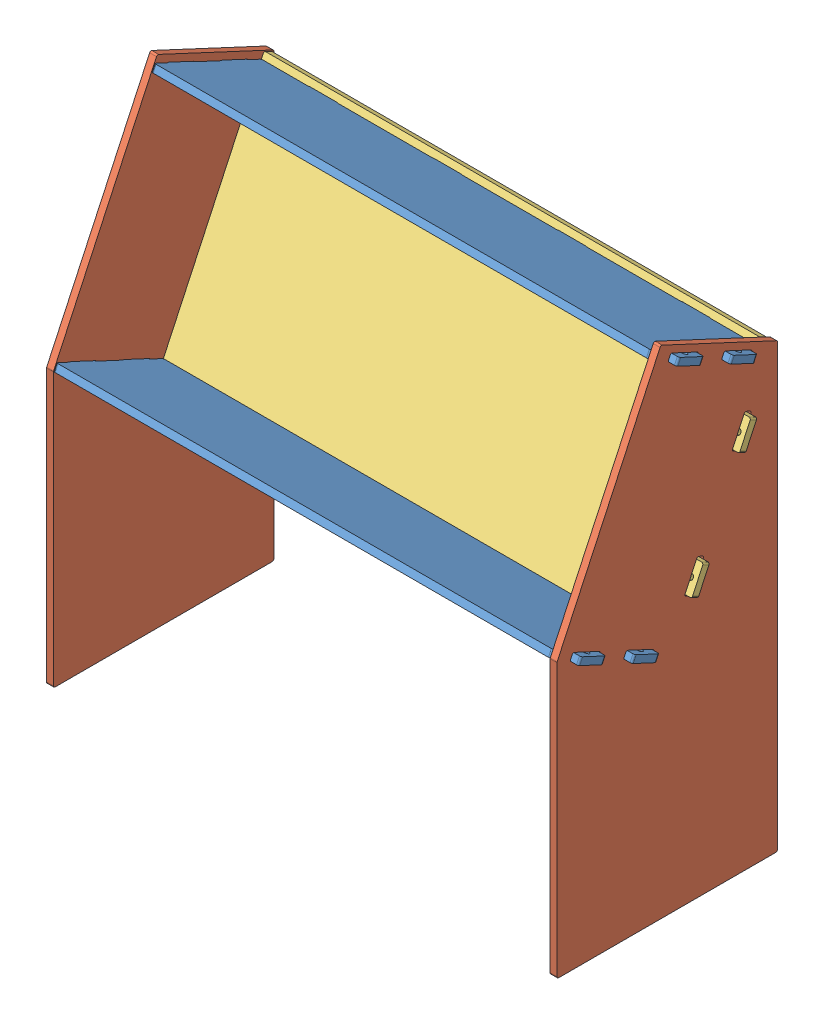
SolidWorks assembly GE-25410, configuration Default. Lengths in mm.
Overall size (971.55 1075.9 915.91).
5 component instances, 3 part files, 15 mates.
Components (placement in the parent):
- GE-25411-1: GE-25411 [30 w>] at (0 467.4625 306.7137) x (1 0 0) z (0 -0.906308 0.422618) size (971.55 244.47 12.7)
- GE-25411-2: GE-25411 [30 w>] at (0 857.1948 124.9785) x (1 0 0) z (0 -0.906308 0.422618) size (971.55 244.47 12.7)
- GE-25413-1: GE-25413 [30 w] at (466.725 708.9665 314.9598) x (0 0.906308 -0.422618) z (1 0 0) size (914.78 584.03 12.7)
- GE-25412-1: GE-25412 [30 w] at (0 613.0072 110.9774) x (1 0 0) z (0 0.422618 0.906308) size (971.55 467.36 12.7)
- GE-25413-4: GE-25413 [30 w] at (-466.725 708.9665 314.9598) x (0 0.906308 -0.422618) z (1 0 0) size (914.78 584.03 12.7)
Mates (geometry in assembly coordinates):
- Coincident1: coincident aligned: plane of Polycarb back panel-1 through (0 613.0072 110.9774) normal (1 0 0)
- Coincident2: coincident anti-aligned: plane of Side panel-1 through (473.075 0 408.672) normal (0 -1 0)
- Coincident3: coincident anti-aligned: plane of Side panel-1 through (473.075 0 0) normal (0 0 -1)
- Coincident4: coincident anti-aligned: plane of Side panel-1 through (460.375 708.9665 314.9598) normal (-1 0 0); plane of Polycarb back panel-1 through (460.375 426.925 204.7554) normal (1 0 0)
- Coincident5: coincident anti-aligned: plane of Side panel-1 through (473.075 805.1472 28.3875) normal (0 -0.422618 -0.906308); plane of Polycarb back panel-1 through (0 615.6908 116.7324) normal (0 0.422618 0.906308)
- Coincident6: coincident anti-aligned: plane of TopBottom panel-1 through (460.375 416.7567 213.0001) normal (1 0 0); plane of Side panel-1 through (460.375 708.9665 314.9598) normal (-1 0 0)
- Coincident7: coincident anti-aligned: plane of TopBottom panel-1 through (457.2 506.6582 405.7945) normal (0 -0.906308 0.422618); plane of Side panel-1 through (473.075 496.93 384.9324) normal (0 0.906308 -0.422618)
- Coincident8: coincident anti-aligned: plane of TopBottom panel-1 through (-457.2 415.4149 210.1226) normal (0 -0.422618 -0.906308); plane of Polycarb back panel-1 through (0 615.6908 116.7324) normal (0 0.422618 0.906308)
- Coincident9: coincident anti-aligned: plane of TopBottom panel-1 through (457.2 518.1683 400.4272) normal (0 0.906308 -0.422618); plane of Polycarb back panel-1 through (373.8562 421.5578 193.2453) normal (0 -0.906308 0.422618)
- Coincident10: coincident anti-aligned: plane of TopBottom panel-2 through (460.375 806.489 31.265) normal (1 0 0); plane of Side panel-1 through (460.375 708.9665 314.9598) normal (-1 0 0)
- Coincident11: coincident anti-aligned: plane of TopBottom panel-2 through (457.2 896.3905 224.0593) normal (0 -0.906308 0.422618); plane of Side panel-1 through (473.075 897.7323 226.9368) normal (0 0.906308 -0.422618)
- Coincident12: coincident anti-aligned: plane of TopBottom panel-2 through (-457.2 805.1472 28.3875) normal (0 -0.422618 -0.906308); plane of Polycarb back panel-1 through (0 615.6908 116.7324) normal (0 0.422618 0.906308)
- Coincident13: coincident anti-aligned: plane of Polycarb back panel-1 through (-460.375 426.925 204.7554) normal (-1 0 0); plane of Side panel-4 through (-460.375 708.9665 314.9598) normal (1 0 0)
- Coincident14: coincident anti-aligned: plane of TopBottom panel-2 through (457.2 896.3905 224.0593) normal (0 -0.906308 0.422618); plane of Side panel-4 through (-460.375 897.7323 226.9368) normal (0 0.906308 -0.422618)
- Coincident15: coincident anti-aligned: plane of Polycarb back panel-1 through (0 615.6908 116.7324) normal (0 0.422618 0.906308); plane of Side panel-4 through (-460.375 805.1472 28.3875) normal (0 -0.422618 -0.906308)
